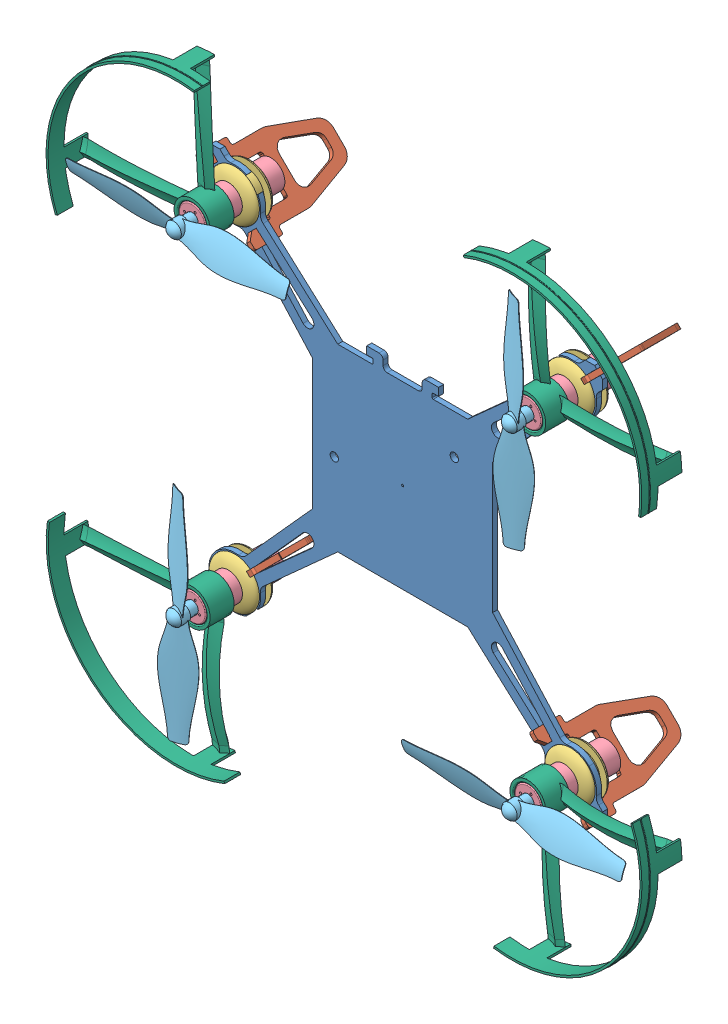
SolidWorks assembly ESP-Drone, configuration 默认. Lengths in mm.
Overall size (170.09 170.09 41.72).
21 component instances, 6 part files, 10 mates.
Components (placement in the parent):
- 底板-1: 底板 [默认] at (-286.201 -195.5785 99.3249) size (99.95 99.95 1.26)
- 脚架-1: 脚架 [默认] at (-319.1593 -304.9546 387.7538) x (0.704518 0.709686 0) z (-0.709686 0.704518 0) size (20.01 27.96 1.26)
- 脚架-2: 脚架 [默认] at (303.1537 -301.4832 387.7538) x (-0.709686 0.704518 0) z (-0.704518 -0.709686 0) size (20.01 27.96 1.26)
- 脚架-3: 脚架 [默认] at (299.6822 320.8298 387.7538) x (-0.704518 -0.709686 0) z (0.709686 -0.704518 0) size (20.01 27.96 1.26)
- 脚架-4: 脚架 [默认] at (-322.6307 317.3584 387.7538) x (0.709686 -0.704518 0) z (0.704518 0.709686 0) size (20.01 27.96 1.26)
- 垫圈-1: 垫圈 [默认] at (32.1995 49.9016 99.0849) x (1 0 0) z (0 -1 0) size (12.31 6.21 12.31)
- 垫圈-2: 垫圈 [默认] at (-51.7026 49.8756 99.0849) x (0 1 0) z (1 0 0) size (12.31 6.21 12.31)
- 垫圈-3: 垫圈 [默认] at (-51.6766 -34.0264 99.0849) x (-1 0 0) z (0 1 0) size (12.31 6.21 12.31)
- 垫圈-4: 垫圈 [默认] at (32.2255 -34.0005 99.0849) x (0 -1 0) z (-1 0 0) size (12.31 6.21 12.31)
- 720空心杯电机-1: 720空心杯电机 [默认] at (32.1995 49.9016 91.2456) x (-0.923728 -0.383049 0) z (-0.383049 0.923728 0) size (7 25 7)
- 720空心杯电机-2: 720空心杯电机 [默认] at (-51.7026 49.8756 91.2456) x (0.383049 -0.923728 0) z (-0.923728 -0.383049 0) size (7 25 7)
- 720空心杯电机-3: 720空心杯电机 [默认] at (-51.6766 -34.0264 91.2456) x (0.923728 0.383049 0) z (0.383049 -0.923728 0) size (7 25 7)
- 720空心杯电机-4: 720空心杯电机 [默认] at (32.2255 -34.0005 91.2456) x (-0.383049 0.923728 0) z (0.923728 0.383049 0) size (7 25 7)
- 55mm螺旋桨-1: 55mm螺旋桨 [Default] at (32.1995 49.9016 105.9984) x (1 0 0) z (0 -1 0) size (11.57 5.73 55.09)
- 55mm螺旋桨-2: 55mm螺旋桨 [Default] at (-51.7026 49.8756 105.9984) x (0 1 0) z (1 0 0) size (11.57 5.73 55.09)
- 55mm螺旋桨-3: 55mm螺旋桨 [Default] at (-51.6766 -34.0264 105.9984) x (-1 0 0) z (0 1 0) size (11.57 5.73 55.09)
- 55mm螺旋桨-4: 55mm螺旋桨 [Default] at (32.2255 -34.0005 105.9984) x (0 -1 0) z (-1 0 0) size (11.57 5.73 55.09)
- 保护架-1: 保护架 [默认] at (32.1995 49.9016 105.2456) x (0.616682 0.787213 0) z (0.787213 -0.616682 0) size (37.11 10.25 56.48)
- 保护架-2: 保护架 [默认] at (-51.7026 49.8756 105.2456) x (-0.787213 0.616682 0) z (0.616682 0.787213 0) size (37.11 10.25 56.48)
- 保护架-3: 保护架 [默认] at (-51.6766 -34.0264 105.2456) x (-0.616682 -0.787213 0) z (-0.787213 0.616682 0) size (37.11 10.25 56.48)
- 保护架-4: 保护架 [默认] at (32.2255 -34.0005 105.2456) x (0.787213 -0.616682 0) z (-0.616682 -0.787213 0) size (37.11 10.25 56.48)
Mates (geometry in assembly coordinates):
- 重合6: coincident: plane of assembly; plane of assembly; plane of 底板-1 through (-14.3387 30.7056 99.3249) normal (0 0 -1); plane of 脚架-1 through (26.1702 44.6967 99.3249) normal (0 0 1)
- 角度4: planar angle = 0.043633 rad: plane of assembly; plane of assembly; plane of 底板-1 through (39.6893 56.48 100.5849) normal (-0.67828 0.734803 0); plane of 脚架-1 through (37.8156 56.4275 101.1956) normal (-0.709686 0.704518 0)
- 同心1: concentric: circle of assembly; circle of assembly; circle of 底板-1; circle of 垫圈-1
- 重合7: coincident: plane of assembly; plane of assembly; plane of 底板-1 through (-14.3387 30.7056 100.5849) normal (0 0 1); plane of 垫圈-1 through (32.1995 54.2616 100.5849) normal (0 0 -1)
- 同心2: concentric: circle of assembly; circle of assembly; circle of 垫圈-1; circle of 720空心杯电机-1; plane of assembly; plane of assembly; plane of 脚架-1; plane of ?
- 重合9: coincident: plane of 脚架-1 through (28.5543 47.0982 91.2456) normal (0 0 1); plane of 720空心杯电机-1 through (32.1995 49.9016 91.2456) normal (0 0 -1)
- 同心3: concentric: circle of 720空心杯电机-1; circle of 55mm螺旋桨-1
- 重合10: coincident: plane of 720空心杯电机-1 through (32.1995 49.9016 111.2456) normal (0 0 1); plane of 55mm螺旋桨-1 through (32.1995 49.9016 111.2456) normal (0 0 -1)
- 同心4: concentric: unknown of 720空心杯电机-1; unknown of 保护架-1
- 重合13: coincident: circle of 720空心杯电机-1; circle of 保护架-1
